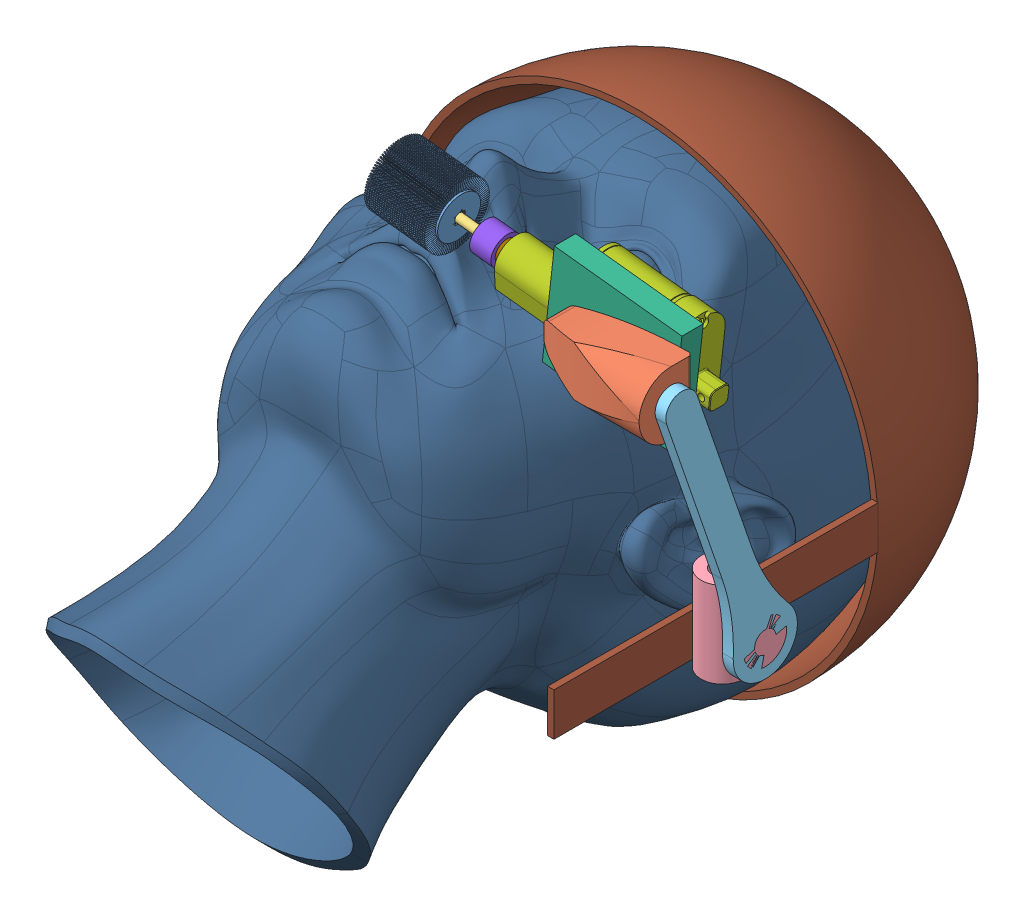
SolidWorks assembly iteration 1, configuration Default. Lengths in mm.
Overall size (256 264.59 367.32).
11 component instances, 11 part files, 21 mates.
Components (placement in the parent):
- BRUSH BRISTLES-1: BRUSH BRISTLES [Default] at (-203.1572 133.6447 117.8229) x (-0.993726 0.111846 0) z (0.070861 0.629584 0.773694) size (30 30 30)
- BRUSH HOLDER-1: BRUSH HOLDER [Default] at (-79.1034 132.7796 142.778) x (0 1 0) z (-1 0 0) size (30 32 63.76)
- BRUSH MOTOR-1: BRUSH MOTOR [Default] at (-203.1572 133.6447 117.8229) x (-0.993726 0.111846 0) z (-0.041573 -0.36937 -0.928352) size (35 6 6)
- POS ADJUSTER-1: POS ADJUSTER [Default] at (-94.1034 39.2893 103.7913) x (1 0 0) z (0 -1 0) size (30 20 40)
- VERTICAL LINK-1: VERTICAL LINK [Default] at (-74.1034 19.2893 103.7913) x (0 0.324889 -0.945752) z (-1 0 0) size (30 142.5 30)
- Part20^iteration 1-1: Part20^iteration 1 [Default] at (-116.6976 131.1019 122.778) x (-0.993726 0.111846 0) z (0 0 1) size (60 50 12.75) (virtual)
- poiston-2: poiston [Default] at (-23.4966 150.4787 152.1393) x (0 0 -1) z (0.993726 -0.111846 0) size (21 41 96.35)
- Part21^iteration 1-1: Part21^iteration 1 [Default] at (-181.2952 131.1841 117.8229) x (-0.993726 0.111846 0) z (0.11098 0.986029 -0.124217) size (10 14 14) (virtual)
- Part23^iteration 1-1: Part23^iteration 1 [Default] at (-188.2513 131.9671 117.8229) x (0.108327 0.962458 -0.248877) z (-0.027836 -0.247315 -0.968535) size (10 60 10) (virtual)
- Head_Female_01-1: Head_Female_01 [Default] at (-218.7754 4.961 120.5828) x (1 0 0) z (0 1 0) size (188.2 344.8 238.6)
- Part28^iteration 1-1: Part28^iteration 1 [Default] at (-217.1034 9.2893 21.0471) size (226 226 264.52) (virtual)
Mates (geometry in assembly coordinates):
- Concentric1: concentric aligned: cylinder of POS ADJUSTER-1 through (-85.4432 19.2893 103.7913) axis (1 0 0) radius 10; cylinder of VERTICAL LINK-1 through (-74.1034 19.2893 103.7913) axis (1 0 0) radius 5
- Coincident1: coincident aligned: plane of POS ADJUSTER-1 through (-79.1034 19.2893 113.7913) normal (-1 0 0); plane of VERTICAL LINK-1 through (-79.1034 132.7796 142.778) normal (-1 0 0)
- Concentric3: concentric aligned: cylinder of BRUSH HOLDER-1 through (-79.1034 132.7796 142.778) axis (1 0 0) radius 5; cylinder of VERTICAL LINK-1 through (-104.1034 132.7796 142.778) axis (1 0 0) radius 5
- Coincident2: coincident anti-aligned: plane of BRUSH HOLDER-1 through (-79.1034 117.7796 155.722) normal (1 0 0); plane of VERTICAL LINK-1 through (-79.1034 132.7796 142.778) normal (-1 0 0)
- Parallel1: parallel anti-aligned: plane of BRUSH HOLDER-1 through (-79.1034 -47.2204 132.778) normal (0 0 -1); plane of POS ADJUSTER-1 through (-94.1034 39.2893 103.7913) normal (0 0 1)
- Concentric5: concentric aligned: cylinder of BRUSH MOTOR-1 through (-223.0317 135.8817 117.8229) axis (0.993726 -0.111846 0) radius 2; cylinder of BRUSH BRISTLES-1 through (-232.9689 137.0001 117.8229) axis (0.993726 -0.111846 0) radius 10
- Coincident4: coincident aligned: plane of BRUSH BRISTLES-1 through (-203.5898 129.8006 120.9907) normal (0.993726 -0.111846 0); plane of BRUSH MOTOR-1 through (-202.9495 135.4898 117.0795) normal (0.993726 -0.111846 0)
- Concentric7: concentric aligned: cylinder of BRUSH HOLDER-1 through (-131.6034 132.7796 125.778) axis (0 0 1) radius 5; cylinder of Part20^iteration 1-1 through (-131.6034 132.7796 82.778) axis (0 0 1) radius 5
- Coincident10: coincident anti-aligned: plane of BRUSH HOLDER-1 through (-79.1034 -47.2204 132.778) normal (0 0 -1); plane of Part20^iteration 1-1 through (-116.6976 131.1019 132.778) normal (0 0 1)
- Parallel2: parallel aligned: plane of Part20^iteration 1-1 through (-89.6819 102.9034 132.778) normal (-0.111846 -0.993726 0); plane of poiston-2 through (-178.6055 120.7742 125.4479) normal (-0.111846 -0.993726 0)
- Lock1: lock: unknown of Part20^iteration 1-1; unknown of poiston-2
- Concentric8: concentric anti-aligned: cylinder of poiston-2 through (-167.5449 129.6365 117.8229) axis (0.993726 -0.111846 0) radius 5; cylinder of Part23^iteration 1-1 through (-128.6277 125.2563 117.8229) axis (-0.993726 0.111846 0) radius 5
- LimitDistance1: limit distance = 10.8371 mm aligned: plane of Part23^iteration 1-1 through (-188.2513 131.9671 117.8229) normal (-0.993726 0.111846 0); plane of poiston-2 through (-177.4821 130.755 117.8229) normal (-0.993726 0.111846 0)
- Concentric9: concentric aligned: cylinder of BRUSH MOTOR-1 through (-223.0317 135.8817 117.8229) axis (0.993726 -0.111846 0) radius 2; cylinder of Part21^iteration 1-1 through (-191.2325 132.3026 117.8229) axis (0.993726 -0.111846 0) radius 7
- Coincident16: coincident aligned: plane of BRUSH MOTOR-1 through (-188.2513 131.9671 117.8229) normal (0.993726 -0.111846 0); plane of Part21^iteration 1-1 through (-188.2513 131.9671 117.8229) normal (0.993726 -0.111846 0)
- Concentric10: concentric anti-aligned: cylinder of Part21^iteration 1-1 through (-188.2513 131.9671 117.8229) axis (0.993726 -0.111846 0) radius 5; cylinder of Part23^iteration 1-1 through (-128.6277 125.2563 117.8229) axis (-0.993726 0.111846 0) radius 5
- Coincident17: coincident anti-aligned: plane of Part21^iteration 1-1 through (-188.2513 131.9671 117.8229) normal (0.993726 -0.111846 0); plane of Part23^iteration 1-1 through (-188.2513 131.9671 117.8229) normal (-0.993726 0.111846 0)
- Parallel4: parallel anti-aligned: plane of Head_Female_01-1 through (-218.7754 4.961 120.5828) normal (0 0 -1); plane of Part28^iteration 1-1 through (-107.1034 9.2893 21.0471) normal (0 0 1)
- Coincident23: coincident aligned: plane of POS ADJUSTER-1 through (-84.1034 -0.7107 103.7913) normal (0 -1 0); plane of Part28^iteration 1-1 through (-104.1034 -0.7107 172.5658) normal (0 -1 0)
- Tangent2: tangent anti-aligned: cylinder of POS ADJUSTER-1 through (-94.1034 -0.7107 103.7913) axis (0 1 0) radius 10; plane of Part28^iteration 1-1 through (-104.1034 9.2893 21.0471) normal (1 0 0)
- Lock2: lock: unknown of POS ADJUSTER-1; unknown of Part28^iteration 1-1
